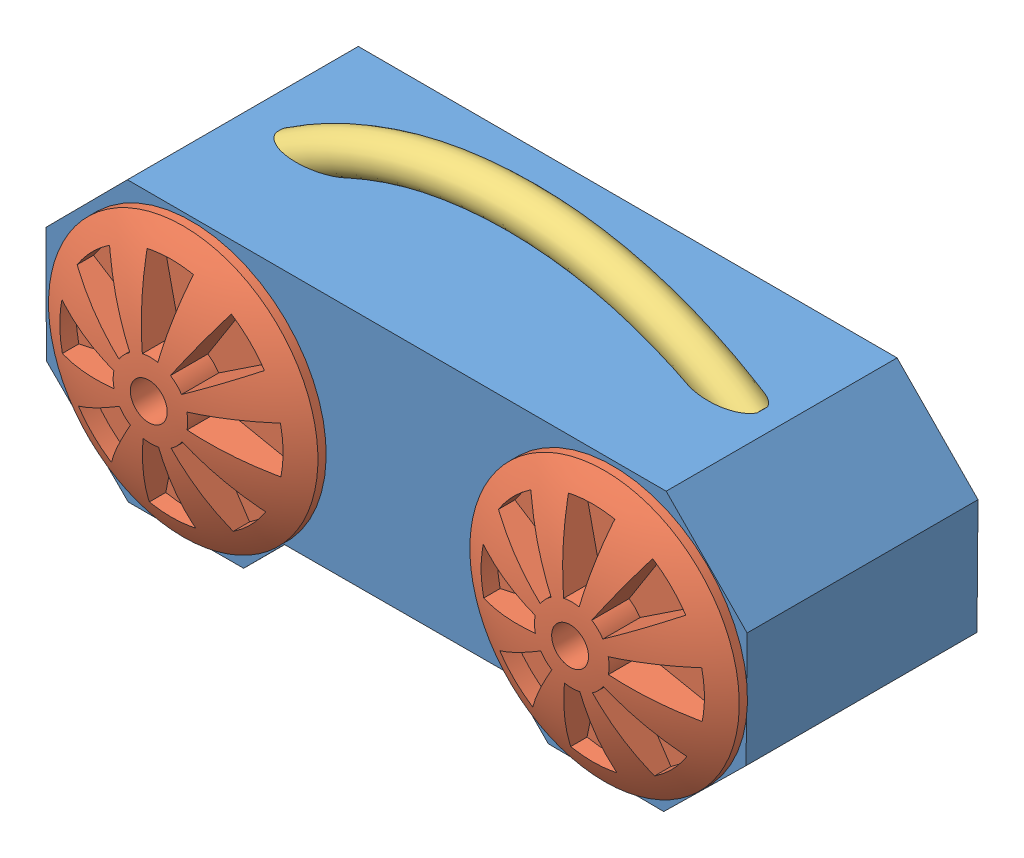
SolidWorks assembly MarkIIISL, configuration Default. Lengths in mm.
Overall size (463 232.99 180.6).
4 component instances, 3 part files, 3 mates.
Components (placement in the parent):
- MarkIIISL-1: MarkIIISL [Default] at (128.1907 292.9226 337.0054) size (462.73 184.19 152.4)
- Speaker6.5-1: Speaker6.5 [Default] at (-20.449 293.3871 495.1239) x (1 0 0) z (0 -1 0) size (177.8 51.46 177.8)
- Speaker6.5-2: Speaker6.5 [Default] at (257.632 292.6085 495.1239) x (1 0 0) z (0 -1 0) size (177.8 51.46 177.8)
- Handle-1: Handle [Default] at (271.323 374.4494 411.2481) x (1 -0.000624 0.000606) z (-0.000624 -1 0) size (324.52 31.18 48.81)
Mates (geometry in assembly coordinates):
- Coincident1: coincident anti-aligned: plane of MarkIIISL-1 through (128.1907 292.9226 489.4054) normal (0 0 1); plane of Speaker6.5-1 through (-109.349 293.3871 489.4054) normal (0 0 -1)
- Coincident2: coincident anti-aligned: plane of MarkIIISL-1 through (128.1907 292.9226 489.4054) normal (0 0 1); plane of Speaker6.5-2 through (168.732 292.6085 489.4054) normal (0 0 -1)
- Coincident3: coincident anti-aligned: plane of MarkIIISL-1 through (-62.7527 384.8179 489.4054) normal (0.000624 1 0); plane of Handle-1 through (271.3293 384.6094 411.2481) normal (-0.000624 -1 0)
